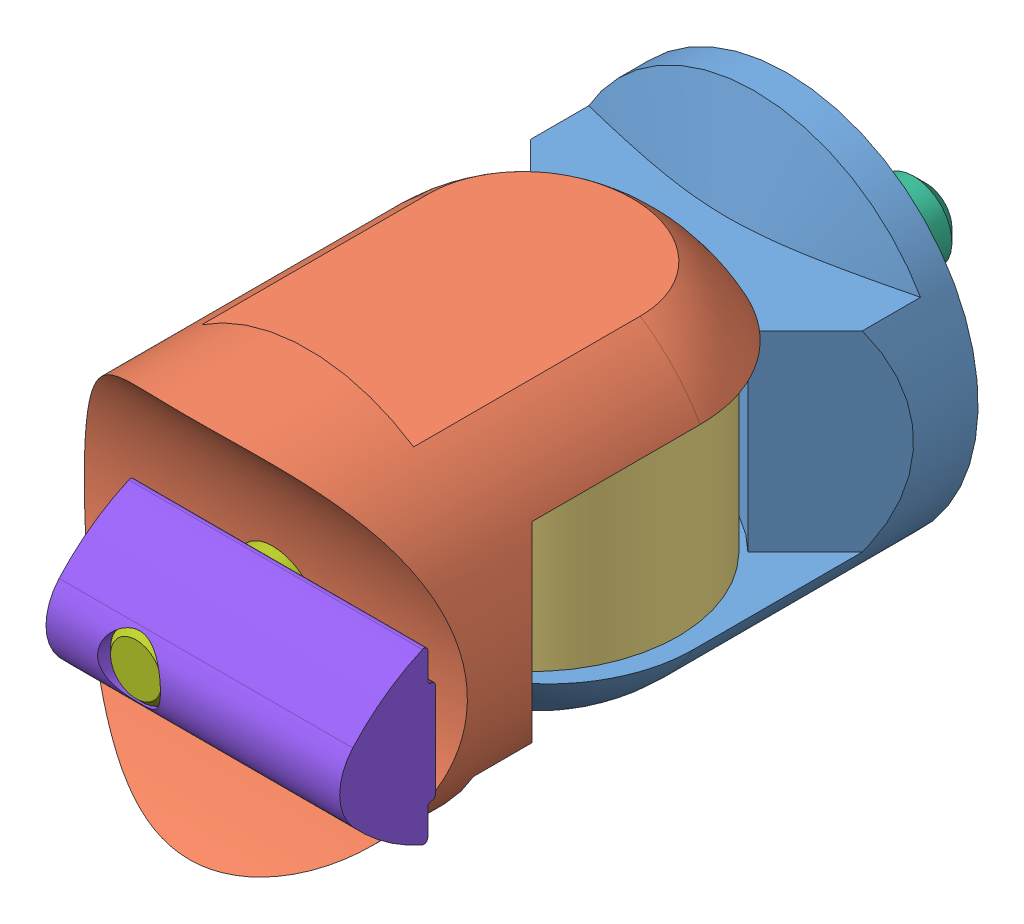
SolidWorks assembly Knieleisten-Winkelverbinder _ 0062028 _ v-oa28, configuration Domyślna. Lengths in mm.
Overall size (31.5 30 62.45).
8 component instances, 8 part files, 0 mates.
Components (placement in the parent):
- Knieleisten-Winkelverbinder-Pfosten_-_0062028-oa20-1: Knieleisten-Winkelverbinder-Pfosten_-_0062028-oa20 [Domyślna] at (0 -40 0) size (30 30 33.3)
- Knieleisten-Winkelverbinder-Handlauf_-_0062028-oa21-1: Knieleisten-Winkelverbinder-Handlauf_-_0062028-oa21 [Domyślna] at (0 -40 -10) x (1 0 0) z (0 0 -1) size (30 30 40.95)
- Knieleisten-Winkelverbinder _ 0062028-oa22-1: Knieleisten-Winkelverbinder _ 0062028-oa22 [Domyślna] at (0 -40 -5) size (23 15 23)
- Senkschraube_DIN_7991_M6x10_-_ 8000748-0062028-oa23-1: Senkschraube_DIN_7991_M6x10_-_ 8000748-0062028-oa23 [Domyślna] at (0 -32.05 -5) x (-1 0 0) z (0 1 0) size (12 12 10)
- Senkschraube_DIN_7991_M6x10_-_ 8000748-0062028-oa24-1: Senkschraube_DIN_7991_M6x10_-_ 8000748-0062028-oa24 [Domyślna] at (0 -47.95 -5) x (0 0 -1) z (0 -1 0) size (12 12 10)
- Senkschraube_DIN_7991_M6x18_-_0062028-oa25-1: Senkschraube_DIN_7991_M6x18_-_0062028-oa25 [Domyślna] at (0 -40 -21.25) x (0 1 0) z (0 0 1) size (12 12 18)
- Senkschraube_DIN_7991_M6x18_-_0062028-oa26-1: Senkschraube_DIN_7991_M6x18_-_0062028-oa26 [Domyślna] at (0 -40 11.25) x (0 1 0) z (0 0 -1) size (12 12 18)
- NUTENSTEIN V 8 ST M6, VERZINKT_-_0048050-oa27-1: NUTENSTEIN V 8 ST M6, VERZINKT_-_0048050-oa27 [Domyślna] at (5 -40 19.6) x (0 -1 0) z (0 0 -1) size (13.3 23 7.5)
